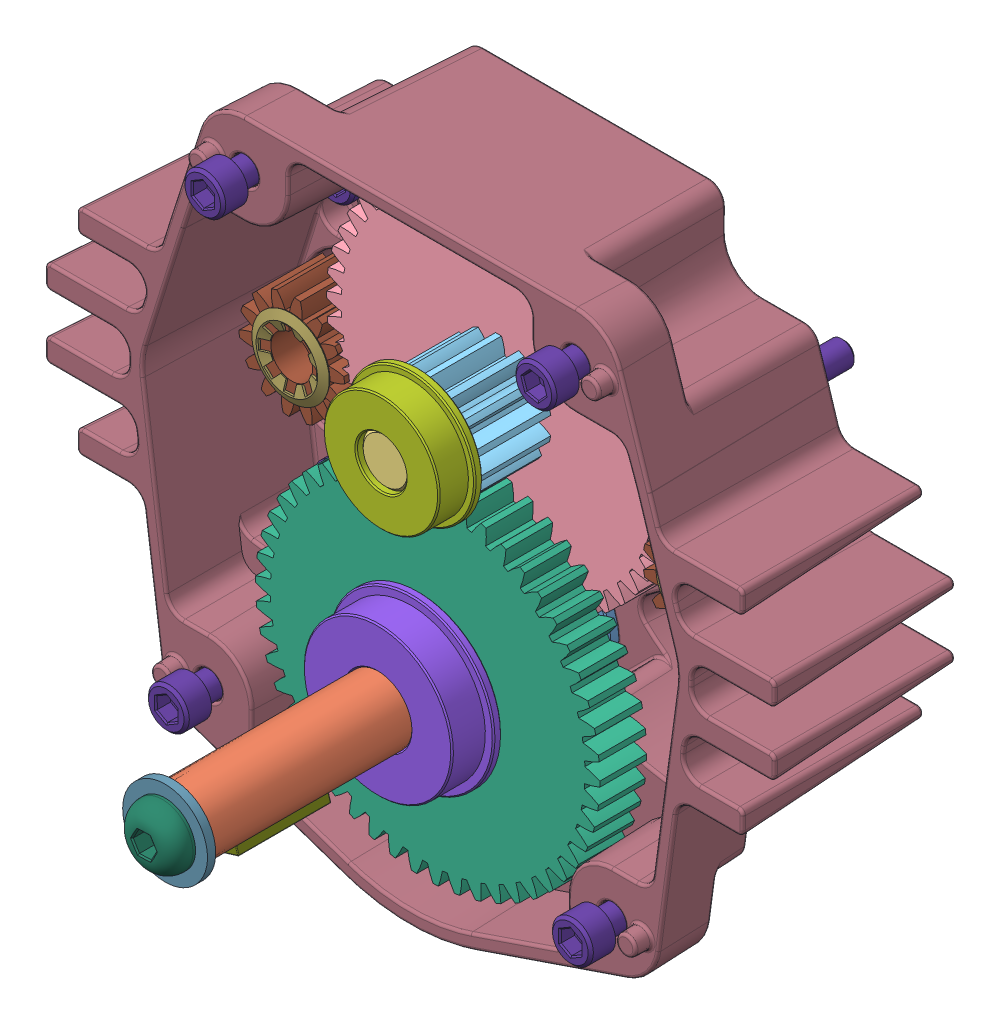
SolidWorks assembly Toughbox-mini, configuration Default. Lengths in mm.
Overall size (139.9 126.02 97.99).
33 component instances, 17 part files, 0 mates.
Components (placement in the parent):
- r6zz-1: r6zz [Default] at (0 40.7162 8.636) x (0.923728 0.383049 0) z (0 0 -1) size (22.23 22.23 7.11)
- r6zz-2: r6zz [Default] at (0 0 8.636) x (0.923728 0.383049 0) z (0 0 -1) size (22.23 22.23 7.11)
- Toughbox_d03-1: Toughbox_d03 [Default] at (41.5117 -4.6979 34.036) x (0.956002 0.293359 0) z (0.293359 -0.956002 0) size (14.66 92.33 12.7)
- Toughbox_d07-1: Toughbox_d07 [Default] at (28.1116 8.6845 34.163) x (0.901009 -0.433799 0) z (-0.433799 -0.901009 0) size (11 38.23 9.52)
- Toughbox_d05-1: Toughbox_d05 [Default] at (0 40.7162 18.796) x (0.901009 -0.433799 0) z (0 0 -1) size (65.97 66.04 10.34)
- Toughbox_d08-1: Toughbox_d08 [Default] at (0 40.7162 18.796) x (0.901009 -0.433799 0) z (0 0 1) size (20.03 20.32 15.25)
- Toughbox_d06-1: Toughbox_d06 [Default] at (0 0 23.4188) x (0.956002 0.293359 0) z (0 0 1) size (65.97 66.04 10.62)
- fr-6-zz-1: fr-6-zz [Default] at (7.4226 32.9743 34.163) x (0.97844 -0.20653 0) z (0 0 1) size (24.69 24.69 7.16)
- fr-8-zz-1: fr-8-zz [Default] at (7.4226 -7.7419 34.036) x (0.97844 -0.20653 0) z (0 0 1) size (31.75 31.75 7.95)
- 10-32_nylock_nut-1: 10-32_nylock_nut [Default] at (140.5562 -27.1657 -65.5923) x (-0.970695 0.240315 0) z (0 0 1) size (11.98 11.69 7.5)
- 10-32_nylock_nut-2: 10-32_nylock_nut [Default] at (63.0862 -27.1657 -65.5923) x (-0.970695 0.240315 0) z (0 0 1) size (11.98 11.69 7.5)
- 10-32_nylock_nut-3: 10-32_nylock_nut [Default] at (70.0712 61.7343 -65.5923) x (-0.970695 0.240315 0) z (0 0 1) size (11.98 11.69 7.5)
- 10-32_nylock_nut-4: 10-32_nylock_nut [Default] at (133.5712 61.7343 -65.5923) x (-0.970695 0.240315 0) z (0 0 1) size (11.98 11.69 7.5)
- 5-16_washer-1: 5-16_washer [Default] at (38.735 28.1699 5.5372) x (0.38418 -0.923258 0) z (0 0 -1) size (17.53 17.53 1.47)
- 5-16_washer-2: 5-16_washer [Default] at (38.735 28.1699 7.0104) x (0.897267 -0.441488 0) z (0 0 -1) size (17.53 17.53 1.47)
- 5-16_washer-3: 5-16_washer [Default] at (-38.735 28.1699 5.5372) x (-0.990116 0.140253 0) z (0 0 1) size (17.53 17.53 1.47)
- 5-16_washer-4: 5-16_washer [Default] at (-38.735 28.1699 4.064) x (-0.681761 0.731575 0) z (0 0 1) size (17.53 17.53 1.47)
- Toughbox_d09-1: Toughbox_d09 [Default] at (38.735 28.1699 19.7104) x (0.897267 -0.441488 0) z (0 0 -1) size (20.03 20.32 12.7)
- Toughbox_d09-2: Toughbox_d09 [Default] at (-38.735 28.1699 19.7104) x (-0.994128 0.108207 0) z (0 0 -1) size (20.03 20.32 12.7)
- 8mm_spring_clip-1: 8mm_spring_clip [Default] at (38.735 28.1699 20.6508) x (0 0 -1) z (0.163192 0.986594 0) size (1.12 14.83 14.83)
- 8mm_spring_clip-2: 8mm_spring_clip [Default] at (-38.735 28.1699 20.6508) x (0 0 -1) z (0.99913 0.041715 0) size (1.12 14.83 14.83)
- Toughbox-mini_d01-5-12-1: Toughbox-mini_d01-5-12 [Default] at origin size (139.9 118.55 41.54)
- 250_washer-1: 250_washer [Default] at (0 0 82.7278) x (-0.851474 -0.524397 0) z (-0.524397 0.851474 0) size (16.26 1.57 16.26)
- 14-20x0500_bhcs-1: 14-20x0500_bhcs [Default] at (0 0 86.7918) x (-0.851474 -0.524397 0) z (-0.524397 0.851474 0) size (11.68 16.79 11.68)
- 125x124x700_key-1: 125x124x700_key [Default] at (0.5563 -8.0923 68.6862) x (0 0 -1) z (-0.956002 -0.293359 0) size (17.78 3.17 3.17)
- 10-32x0625_shcs-1: 10-32x0625_shcs [Default] at (38.735 53.5699 11.8872) x (-0.564778 -0.825243 0) z (-0.825243 0.564778 0) size (7.82 20.65 7.82)
- 10-32x0625_shcs-2: 10-32x0625_shcs [Default] at (-31.75 70.5879 43.7642) x (0.507484 -0.861661 0) z (-0.861661 -0.507484 0) size (7.82 20.65 7.82)
- 10-32x0625_shcs-3: 10-32x0625_shcs [Default] at (-38.735 -18.3121 43.7642) x (0.507484 -0.861661 0) z (-0.861661 -0.507484 0) size (7.82 20.65 7.82)
- 10-32x0625_shcs-4: 10-32x0625_shcs [Default] at (38.735 -18.3121 43.7642) x (0.507484 -0.861661 0) z (-0.861661 -0.507484 0) size (7.82 20.65 7.82)
- 10-32x0625_shcs-5: 10-32x0625_shcs [Default] at (31.75 70.5879 43.7642) x (0.740711 -0.671824 0) z (-0.671824 -0.740711 0) size (7.82 20.65 7.82)
- 10-32x0625_shcs-6: 10-32x0625_shcs [Default] at (38.735 2.7699 11.8872) x (-0.564778 -0.825243 0) z (-0.825243 0.564778 0) size (7.82 20.65 7.82)
- 10-32x0625_shcs-7: 10-32x0625_shcs [Default] at (-38.735 53.5699 11.8872) x (-0.966277 -0.257503 0) z (-0.257503 0.966277 0) size (7.82 20.65 7.82)
- 10-32x0625_shcs-8: 10-32x0625_shcs [Default] at (-38.735 2.7699 11.8872) x (-0.99652 0.083357 0) z (0.083357 0.99652 0) size (7.82 20.65 7.82)
